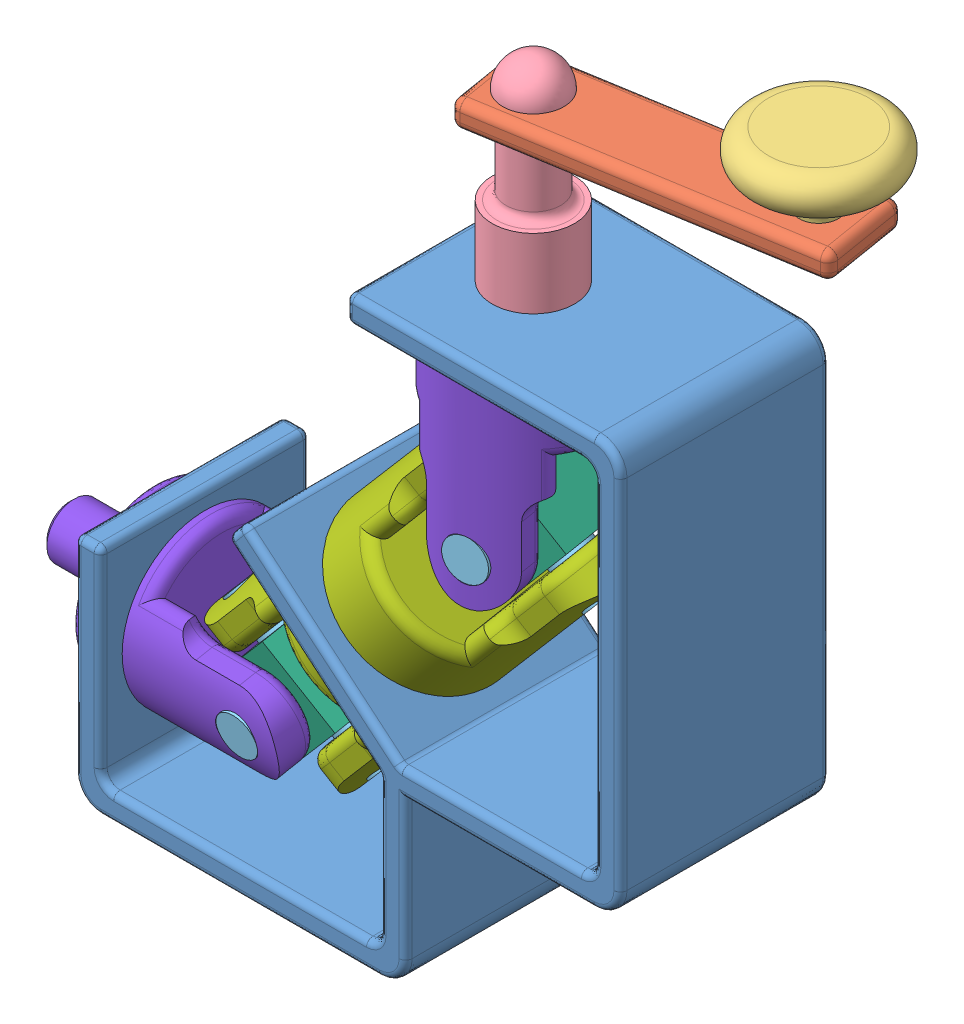
SolidWorks assembly Assem1, configuration Default. Lengths in mm.
Overall size (179.97 186.2 50.57).
11 component instances, 8 part files, 25 mates.
Components (placement in the parent):
- Pieza11.1-1: Pieza11.1 [Default] at (-20.954 0.0595 131.4344) size (125.3 132.2 48)
- Pieza11.2-1: Pieza11.2 [Default] at (124.3424 164.2595 86.7774) x (-0.98675 0 0.162249) z (-0.162249 0 -0.98675) size (76 6 20)
- Pieza11.3-1: Pieza11.3 [Default] at (116.5908 164.2595 98.1862) x (0.99627 0 -0.086294) z (0.086294 0 0.99627) size (32 22 32)
- Pieza11.4-1: Pieza11.4 [Default] at (60.346 132.2595 107.4344) x (-0.162249 0 -0.98675) z (0.98675 0 -0.162249) size (18.9 45 18.9)
- Pieza11.5-1: Pieza11.5 [Default] at (60.346 87.6095 107.4344) x (-0.636514 -0.764131 0.10466) z (0.754006 -0.645061 -0.123979) size (9.4 38 38)
- Pieza11.5-2: Pieza11.5 [Default] at (10.9402 29.8595 107.4344) x (0.656868 0.740454 0.142313) z (0 -0.188743 0.982026) size (9.4 38 38)
- Pieza11.6-1: Pieza11.6 [Default] at (75.0973 88.7407 114.6365) x (-0.636514 -0.764131 0.10466) z (0.754006 -0.645061 -0.123979) size (19 19 19)
- Pieza11.6-2: Pieza11.6 [Default] at (11.863 18.4902 95.5754) x (0.656868 0.740454 0.142313) z (0.754006 -0.645061 -0.123979) size (19 19 19)
- Pieza11.7-1: Pieza11.7 [Default] at (35.6431 58.7345 107.4344) x (-0.094208 0.080596 -0.992285) z (0.754006 -0.645061 -0.123979) size (38.1 95 38.1)
- Pieza11.8-1: Pieza11.8 [Default] at (60.346 125.6095 107.4344) x (-0.98675 0 0.162249) z (0.162249 0 0.98675) size (38.1 66.5 38.1)
- Pieza11.8-2: Pieza11.8 [Default] at (-27.0598 29.8595 107.4344) x (0 -0.982026 -0.188743) z (0 -0.188743 0.982026) size (38.1 66.5 38.1)
Mates (geometry in assembly coordinates):
- Concentric25: concentric aligned: cylinder of Pieza11.5-1 through (63.4288 87.6095 126.1827) axis (-0.162249 0 -0.98675) radius 4.7; cylinder of Pieza11.6-1 through (64.0672 87.6095 130.0656) axis (-0.162249 0 -0.98675) radius 4.75
- Concentric26: concentric aligned: cylinder of Pieza11.5-1 through (46.0199 99.8657 109.79) axis (0.754006 -0.645061 -0.123979) radius 4.7; cylinder of Pieza11.6-1 through (53.183 93.7376 108.6122) axis (0.754006 -0.645061 -0.123979) radius 4.75
- Concentric27: concentric anti-aligned: cylinder of Pieza11.5-2 through (25.2663 17.6033 105.0788) axis (-0.754006 0.645061 0.123979) radius 4.7; cylinder of Pieza11.6-2 through (3.7771 35.9876 108.6122) axis (0.754006 -0.645061 -0.123979) radius 4.75
- Concentric28: concentric aligned: cylinder of Pieza11.5-2 through (10.9402 33.4456 88.7759) axis (0 -0.188743 0.982026) radius 4.7; circle of Pieza11.6-2
- Concentric30: concentric aligned: circle of Pieza11.1-1; cylinder of Pieza11.8-2 through (-11.0598 29.8595 107.4344) axis (-1 0 0) radius 19.05
- Concentric31: concentric aligned: circle of Pieza11.1-1; cylinder of Pieza11.8-1 through (60.346 144.6095 107.4344) axis (0 -1 0) radius 6.25
- Perpendicular1: perpendicular: cylinder of Pieza11.7-1 through (74.7106 75.3204 105.0725) axis (-0.754006 0.645061 0.123979) radius 4.75; cylinder of Pieza11.8-1 through (57.255 87.6095 88.6358) axis (0.162249 0 0.98675) radius 4.75
- Perpendicular2: perpendicular: cylinder of Pieza11.7-1 through (25.3047 17.5704 105.0725) axis (-0.754006 0.645061 0.123979) radius 4.75; cylinder of Pieza11.8-2 through (10.9402 33.4553 88.7258) axis (0 -0.188743 0.982026) radius 4.75
- Concentric34: concentric aligned: cylinder of Pieza11.5-2 through (25.2663 17.6033 105.0788) axis (-0.754006 0.645061 0.123979) radius 4.7; cylinder of Pieza11.7-1 through (25.3047 17.5704 105.0725) axis (-0.754006 0.645061 0.123979) radius 4.75
- Concentric35: concentric aligned: cylinder of Pieza11.5-2 through (10.9402 33.4456 88.7759) axis (0 -0.188743 0.982026) radius 4.7; cylinder of Pieza11.8-2 through (10.9402 33.4553 88.7258) axis (0 -0.188743 0.982026) radius 4.75
- Width1: width aligned: plane of Pieza11.6-2 through (-2.4631 27.1602 116.5895) normal (-0.754006 0.645061 0.123979); plane of Pieza11.6-2 through (11.863 14.9041 114.2339) normal (0.754006 -0.645061 -0.123979); plane of Pieza11.7-1 through (14.0057 14.7347 122.0971) normal (-0.754006 0.645061 0.123979); plane of Pieza11.7-1 through (-1.4514 27.9585 124.6387) normal (0.754006 -0.645061 -0.123979)
- Width2: width anti-aligned: plane of Pieza11.6-2 through (11.863 14.9041 114.2339) normal (0 -0.188743 0.982026); plane of Pieza11.6-2 through (11.863 18.4902 95.5754) normal (0 0.188743 -0.982026); plane of Pieza11.8-2 through (20.4402 43.6937 120.5309) normal (0 0.188743 -0.982026); plane of Pieza11.8-2 through (20.4402 47.5629 100.3994) normal (0 -0.188743 0.982026)
- Concentric36: concentric anti-aligned: cylinder of Pieza11.5-1 through (46.0199 99.8657 109.79) axis (0.754006 -0.645061 -0.123979) radius 4.7; cylinder of Pieza11.7-1 through (74.7106 75.3204 105.0725) axis (-0.754006 0.645061 0.123979) radius 4.75
- Width3: width aligned: plane of Pieza11.6-1 through (72.0146 88.7407 95.8882) normal (0.754006 -0.645061 -0.123979); plane of Pieza11.6-1 through (57.6885 100.9968 98.2438) normal (-0.754006 0.645061 0.123979); plane of Pieza11.7-1 through (60.3059 100.146 124.6387) normal (0.754006 -0.645061 -0.123979); plane of Pieza11.7-1 through (75.7631 86.9222 122.0971) normal (-0.754006 0.645061 0.123979)
- Concentric38: concentric anti-aligned: cylinder of Pieza11.5-1 through (63.4288 87.6095 126.1827) axis (-0.162249 0 -0.98675) radius 4.7; cylinder of Pieza11.8-1 through (57.255 87.6095 88.6358) axis (0.162249 0 0.98675) radius 4.75
- Width5: width anti-aligned: plane of Pieza11.8-1 through (74.5276 78.1095 94.7149) normal (0.162249 0 0.98675); plane of Pieza11.8-1 through (77.8537 78.1095 114.9433) normal (-0.162249 0 -0.98675); plane of Pieza11.6-1 through (72.0146 88.7407 95.8882) normal (-0.162249 0 -0.98675); plane of Pieza11.6-1 through (75.0973 88.7407 114.6365) normal (0.162249 0 0.98675)
- Concentric39: concentric aligned: cylinder of Pieza11.4-1 through (60.346 148.2595 107.4344) axis (0 -1 0) radius 9.45; cylinder of Pieza11.8-1 through (60.346 144.6095 107.4344) axis (0 -1 0) radius 6.25
- Parallel5: parallel anti-aligned: plane of Pieza11.4-1 through (54.7384 144.9595 104.1474) normal (0.98675 0 -0.162249); plane of Pieza11.8-1 through (56.6094 132.1095 112.4444) normal (-0.98675 0 0.162249)
- Concentric40: concentric anti-aligned: cylinder of Pieza11.4-1 through (51.0203 138.6095 108.9678) axis (0.98675 0 -0.162249) radius 1.25; cylinder of Pieza11.8-1 through (56.8924 138.6095 108.0023) axis (-0.98675 0 0.162249) radius 1.25
- Coincident14: coincident anti-aligned: plane of Pieza11.1-1 through (104.346 132.2595 83.4344) normal (0 1 0); plane of Pieza11.4-1 through (60.346 132.2595 107.4344) normal (0 -1 0)
- Concentric41: concentric anti-aligned: cylinder of Pieza11.2-1 through (60.346 147.2268 107.4344) axis (0 1 0) radius 6.35; cylinder of Pieza11.4-1 through (60.346 170.2595 107.4344) axis (0 -1 0) radius 6.25
- Coincident15: coincident anti-aligned: plane of Pieza11.2-1 through (56.0474 147.2268 112.1082) normal (0.98675 0 -0.162249); plane of Pieza11.4-1 through (54.8038 163.9095 104.5453) normal (-0.98675 0 0.162249)
- Coincident16: coincident anti-aligned: plane of Pieza11.2-1 through (124.3424 170.2595 86.7774) normal (0 1 0); plane of Pieza11.4-1 through (60.346 170.2595 107.4344) normal (0 -1 0)
- Concentric42: concentric aligned: cylinder of Pieza11.2-1 through (116.5908 147.2268 98.1862) axis (0 1 0) radius 2.4; cylinder of Pieza11.3-1 through (116.5908 193.1768 98.1862) axis (0 1 0) radius 2.25
- Coincident17: coincident anti-aligned: plane of Pieza11.2-1 through (124.3424 170.2595 86.7774) normal (0 1 0); plane of Pieza11.3-1 through (118.8324 170.2595 97.9921) normal (0 -1 0)
